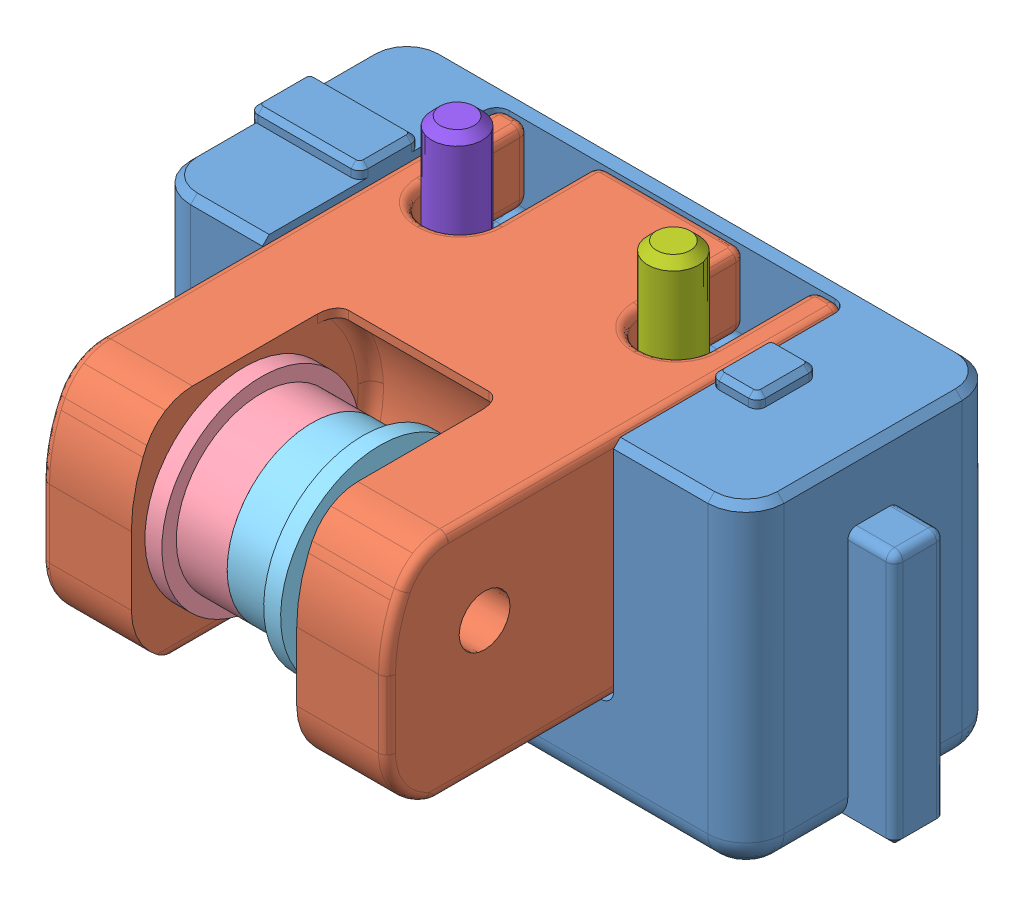
SolidWorks assembly safer_z_idlers, configuration Default. Lengths in mm.
Overall size (37.74 23.16 30.37).
8 component instances, 8 part files, 14 mates.
Components (placement in the parent):
- safer_z_idler-1: safer_z_idler [Default] at (-14.1739 10.4455 393.5518) size (37.74 19.41 15)
- z_tensioner_heatset-1: z_tensioner_heatset [pinned] at (-19.0011 -25.5617 381.355) size (20.5 13.42 27.03)
- Copy of M3 Threaded Insert (6)^safer_z_idlers-1: Copy of M3 Threaded Insert (6)^safer_z_idlers [Default] at (7.111 19.8454 32.3355) x (-1 0 0) z (0 -1 0) size (5.56 3.8 5.56) (virtual)
- Copy of f623-rs (2) (2)^safer_z_idlers-1: Copy of f623-rs (2) (2)^safer_z_idlers [Default] at (5.336 23.9955 45.9552) x (0 0.46978 0.882784) z (1 0 0) size (11.7 11.7 4) (virtual)
- Copy (2) of f623-rs (2) (2)^safer_z_idlers-2: Copy (2) of f623-rs (2) (2)^safer_z_idlers [Default] at (8.936 23.9955 45.9552) x (0 0.917397 0.397974) z (-1 0 0) size (11.7 11.7 4) (virtual)
- Copy of M3x12 BHCS (1) (1)^safer_z_idlers-2: Copy of M3x12 BHCS (1) (1)^safer_z_idlers [Default] at (7.111 19.8454 31.3768) x (0 -1 0) z (0 0 -1) size (5.7 5.7 13.65) (virtual)
- Copy of M3x20 BHCS (2) (1) (1)^safer_z_idlers-1: Copy of M3x20 BHCS (2) (1) (1)^safer_z_idlers [Default] at (13.486 12.3464 31.0018) x (0.837169 0 0.546944) z (0 1 0) size (5.7 5.7 21.65) (virtual)
- Copy (2) of M3x20 BHCS (2) (1) (1)^safer_z_idlers-2: Copy (2) of M3x20 BHCS (2) (1) (1)^safer_z_idlers [Default] at (0.736 12.3464 31.0018) x (0.837169 0 0.546944) z (0 1 0) size (5.7 5.7 21.65) (virtual)
Mates (geometry in assembly coordinates):
- Concentric6: concentric aligned: cylinder of safer_z_idler-1 through (7.111 19.8454 23.5018) axis (0 0 -1) radius 1.7; cylinder of z_tensioner_heatset-1 through (7.111 19.8454 36.3815) axis (0 0 -1) radius 2.35
- Concentric8: concentric anti-aligned: cylinder of z_tensioner_heatset-1 through (7.111 19.8454 36.3815) axis (0 0 -1) radius 2.35; cylinder of Copy of M3 Threaded Insert (6)^safer_z_idlers-1 through (7.111 19.8454 36.1815) axis (0 0 1) radius 2.525
- Coincident4: coincident aligned: plane of z_tensioner_heatset-1 through (1.936 29.5954 32.3815) normal (0 0 -1); plane of Copy of M3 Threaded Insert (6)^safer_z_idlers-1 through (7.111 19.8454 32.3815) normal (0 0 -1)
- Concentric9: concentric anti-aligned: cylinder of z_tensioner_heatset-1 through (17.361 23.9955 46.0012) axis (-1 0 0) radius 1.5; cylinder of Copy of f623-rs (2) (2)^safer_z_idlers-1 through (7.336 23.9955 46.0012) axis (1 0 0) radius 1.5
- Concentric10: concentric aligned: cylinder of z_tensioner_heatset-1 through (17.361 23.9955 46.0012) axis (-1 0 0) radius 1.5; cylinder of Copy (2) of f623-rs (2) (2)^safer_z_idlers-2 through (6.936 23.9955 46.0012) axis (-1 0 0) radius 1.5
- Coincident5: coincident anti-aligned: plane of Copy of f623-rs (2) (2)^safer_z_idlers-1 through (7.136 26.4278 39.6093) normal (1 0 0); plane of Copy (2) of f623-rs (2) (2)^safer_z_idlers-2 through (7.136 17.8176 48.9349) normal (-1 0 0)
- Distance1: distance = 0.3 mm anti-aligned: plane of Copy of f623-rs (2) (2)^safer_z_idlers-1 through (3.136 20.1995 47.9753) normal (-1 0 0); plane of z_tensioner_heatset-1 through (2.836 23.9955 45.9552) normal (1 0 0)
- Parallel3: parallel aligned: plane of safer_z_idler-1 through (8.1609 29.4964 39.9367) normal (0 1 0); plane of z_tensioner_heatset-1 through (1.936 29.4964 49.423) normal (0 1 0)
- Concentric13: concentric: cylinder of safer_z_idler-1 through (7.111 19.8454 23.5018) axis (0 0 -1) radius 1.7; cylinder of Copy of M3x12 BHCS (1) (1)^safer_z_idlers-2 through (7.111 19.8454 27.0018) axis (0 0 1) radius 1.5
- Coincident11: coincident anti-aligned: plane of safer_z_idler-1 through (-8.3765 31.5954 27.0018) normal (0 0 -1); plane of Copy of M3x12 BHCS (1) (1)^safer_z_idlers-2 through (7.111 16.9954 27.0018) normal (0 0 1)
- Concentric14: concentric: cylinder of safer_z_idler-1 through (13.486 10.8454 31.0018) axis (0 -1 0) radius 1.7; cylinder of Copy of M3x20 BHCS (2) (1) (1)^safer_z_idlers-1 through (13.486 7.9904 31.0018) axis (0 -1 0) radius 1.5
- Concentric15: concentric: cylinder of safer_z_idler-1 through (0.736 10.8454 31.0018) axis (0 -1 0) radius 1.7; cylinder of Copy (2) of M3x20 BHCS (2) (1) (1)^safer_z_idlers-2 through (0.736 38.9964 31.0018) axis (0 -1 0) radius 1.5
- Coincident12: coincident anti-aligned: plane of safer_z_idler-1 through (0.736 13.9964 31.0018) normal (0 -1 0); plane of Copy (2) of M3x20 BHCS (2) (1) (1)^safer_z_idlers-2 through (-0.8228 13.9964 33.3878) normal (0 1 0)
- Coincident13: coincident anti-aligned: plane of safer_z_idler-1 through (13.486 13.9964 31.0018) normal (0 -1 0); plane of Copy of M3x20 BHCS (2) (1) (1)^safer_z_idlers-1 through (11.9272 13.9964 33.3878) normal (0 1 0)
